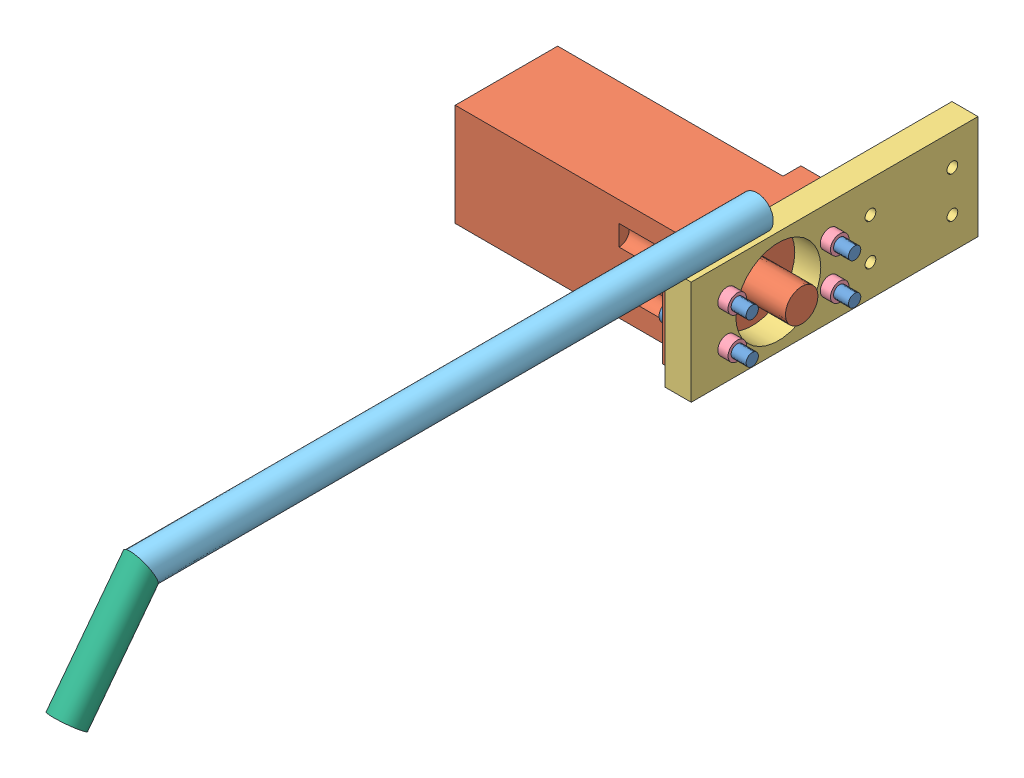
SolidWorks assembly 76model, configuration Default. Lengths in mm.
Overall size (290 139.18 892.13).
13 component instances, 6 part files, 21 mates.
Components (placement in the parent):
- Long2Screw-1: Long2Screw [Default] at (-290.0277 244.8488 24.2694) x (0 -1 0) z (0 0 1) size (18 82 18)
- Long2Screw-2: Long2Screw [Default] at (-290.0277 204.8488 24.2694) x (0 -1 0) z (0 0 1) size (18 82 18)
- Long2Screw-3: Long2Screw [Default] at (-290.0277 244.8488 124.2694) x (0 -1 0) z (0 0 1) size (18 82 18)
- Long2Screw-4: Long2Screw [Default] at (-290.0277 204.8488 124.2694) x (0 -1 0) z (0 0 1) size (18 82 18)
- HydraulicMotor-1: HydraulicMotor [Default] at (-498.0277 174.8488 124.2694) size (288.26 100 135)
- RotationSupportFlat-1: RotationSupportFlat [Default] at (-258.0277 173.8488 -120.7306) x (0 1 0) z (0 0 -1) size (101.6 25.4 280)
- MediumNut-3: MediumNut [Default] at (-232.6277 244.8488 124.2694) x (0 -1 0) z (0 0 1) size (18 10 18)
- MediumNut-4: MediumNut [Default] at (-232.6277 244.8488 24.2694) x (0 -1 0) z (0 0 1) size (18 10 18)
- MediumNut-5: MediumNut [Default] at (-222.6277 204.8488 124.2694) x (0 1 0) z (0 0 1) size (18 10 18)
- MediumNut-6: MediumNut [Default] at (-222.6277 204.8488 24.2694) x (0 1 0) z (0 0 1) size (18 10 18)
- 54model-1: 54model [Default] at (-244.7505 283.5848 399.5277) x (-0.989814 0.142363 0) z (0.142363 0.989814 0) size (52.2 688.33 125.38)
  - OperationHandle-1: OperationHandle [Default] at (0.8634 -316.4583 7.4649) size (31.8 609.6 31.8)
  - OperationHandleSupport-1: OperationHandleSupport [Default] at (-12.6679 357.5672 -85.8841) x (-0.967918 0.11237 0.22474) z (0.22474 0.787167 0.574334) size (31.8 127 31.8)
Mates (geometry in assembly coordinates):
- Concentric1: concentric anti-aligned: cylinder of HydraulicMotor-1 through (-209.7677 224.8488 74.2694) axis (-1 0 0) radius 15.9; cylinder of RotationSupportFlat-1 through (-258.0277 224.8488 74.2694) axis (1 0 0) radius 41.5
- Concentric2: concentric aligned: circle of HydraulicMotor-1; circle of RotationSupportFlat-1
- Coincident1: coincident anti-aligned: plane of HydraulicMotor-1; plane of RotationSupportFlat-1
- Coincident6: coincident anti-aligned: plane of HydraulicMotor-1 through (-278.0277 174.8488 141.7694) normal (-1 0 0); circle of Long2Screw-4
- Coincident7: coincident anti-aligned: plane of HydraulicMotor-1 through (-278.0277 174.8488 141.7694) normal (-1 0 0); circle of Long2Screw-3
- Coincident8: coincident anti-aligned: plane of HydraulicMotor-1 through (-278.0277 174.8488 141.7694) normal (-1 0 0); circle of Long2Screw-2
- Coincident9: coincident anti-aligned: plane of HydraulicMotor-1 through (-278.0277 174.8488 141.7694) normal (-1 0 0); circle of Long2Screw-1
- Concentric4: concentric anti-aligned: cylinder of Long2Screw-4 through (-208.0277 204.8488 124.2694) axis (-1 0 0) radius 6; circle of HydraulicMotor-1
- Concentric5: concentric anti-aligned: cylinder of Long2Screw-3 through (-208.0277 244.8488 124.2694) axis (-1 0 0) radius 6; circle of HydraulicMotor-1
- Concentric6: concentric anti-aligned: cylinder of Long2Screw-2 through (-208.0277 204.8488 24.2694) axis (-1 0 0) radius 6; circle of HydraulicMotor-1
- Concentric7: concentric anti-aligned: cylinder of Long2Screw-1 through (-208.0277 244.8488 24.2694) axis (-1 0 0) radius 6; circle of HydraulicMotor-1
- Concentric8: concentric aligned: cylinder of Long2Screw-2 through (-208.0277 204.8488 24.2694) axis (-1 0 0) radius 6; cylinder of MediumNut-6 through (-222.6277 204.8488 24.2694) axis (-1 0 0) radius 6
- Coincident10: coincident aligned: cylinder of Long2Screw-4 through (-208.0277 204.8488 124.2694) axis (-1 0 0) radius 6; circle of MediumNut-5
- Coincident11: coincident anti-aligned: cylinder of Long2Screw-3 through (-208.0277 244.8488 124.2694) axis (-1 0 0) radius 6; circle of MediumNut-3
- Coincident12: coincident anti-aligned: cylinder of Long2Screw-1 through (-208.0277 244.8488 24.2694) axis (-1 0 0) radius 6; circle of MediumNut-4
- Coincident13: coincident anti-aligned: plane of RotationSupportFlat-1 through (-232.6277 173.8488 159.2694) normal (1 0 0); plane of MediumNut-3 through (-232.6277 244.8488 124.2694) normal (-1 0 0)
- Coincident14: coincident anti-aligned: plane of RotationSupportFlat-1 through (-232.6277 173.8488 159.2694) normal (1 0 0); plane of MediumNut-6 through (-232.6277 204.8488 24.2694) normal (-1 0 0)
- Coincident15: coincident aligned: plane of RotationSupportFlat-1 through (-232.6277 173.8488 159.2694) normal (1 0 0); circle of MediumNut-4
- Coincident16: coincident anti-aligned: plane of RotationSupportFlat-1 through (-232.6277 173.8488 159.2694) normal (1 0 0); plane of MediumNut-5 through (-232.6277 204.8488 124.2694) normal (-1 0 0)
- Parallel1: parallel anti-aligned: line of RotationSupportFlat-1 through (-258.0277 275.4488 -120.7306) axis (0 0 1); cylinder of 54model-1/OperationHandle-1 through (-244.5424 291.0965 692.6694) axis (0 0 -1) radius 15.9
- Distance1: distance = 76.2 mm anti-aligned: plane of RotationSupportFlat-1 through (-232.6277 173.8488 159.2694) normal (0 0 1); plane of 54model-1/OperationHandle-1 through (-244.5424 291.0965 83.0694) normal (0 0 -1)
